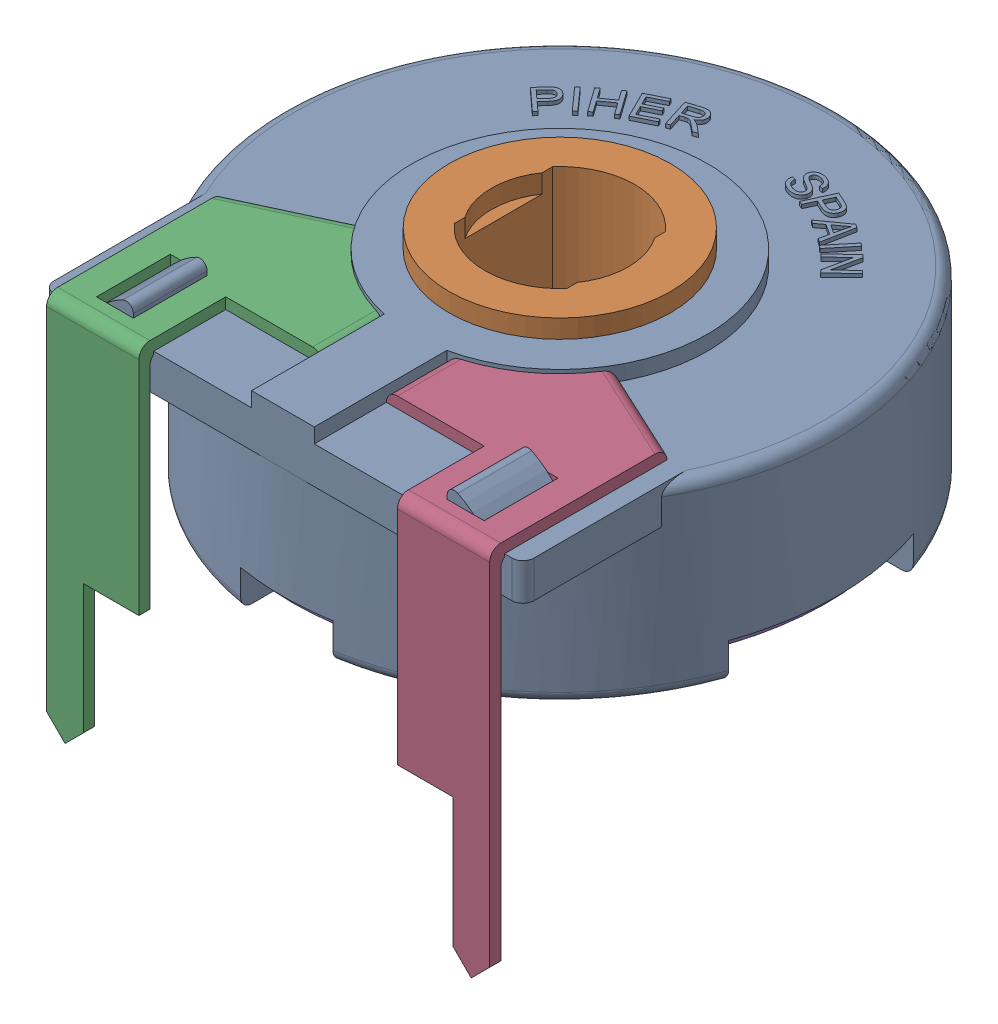
SolidWorks assembly Trimmer_Piher_PT-15, configuration Default. Lengths in mm.
Overall size (15 10.9 15.4).
4 component instances, 3 part files, 0 mates.
Components (placement in the parent):
- Trimmer_Piher_PT-15(2)-1: Trimmer_Piher_PT-15(2) [Default] at origin size (15 10.9 15.4)
  - Corps_PT-15-1: Corps_PT-15 [Default] at (-10.6222 0.2667 0) size (15 5.61 15)
  - Axe-1: Axe [Default] at (-10.6222 5.6667 0) x (-1 0 0) z (0 1 0) size (7.5 7.5 5.7)
  - Broche 1-1: Broche 1 [Default] at (-10.6222 5.2667 0) x (-1 0 0) z (0 1 0) size (14.44 15.12 10.3)
